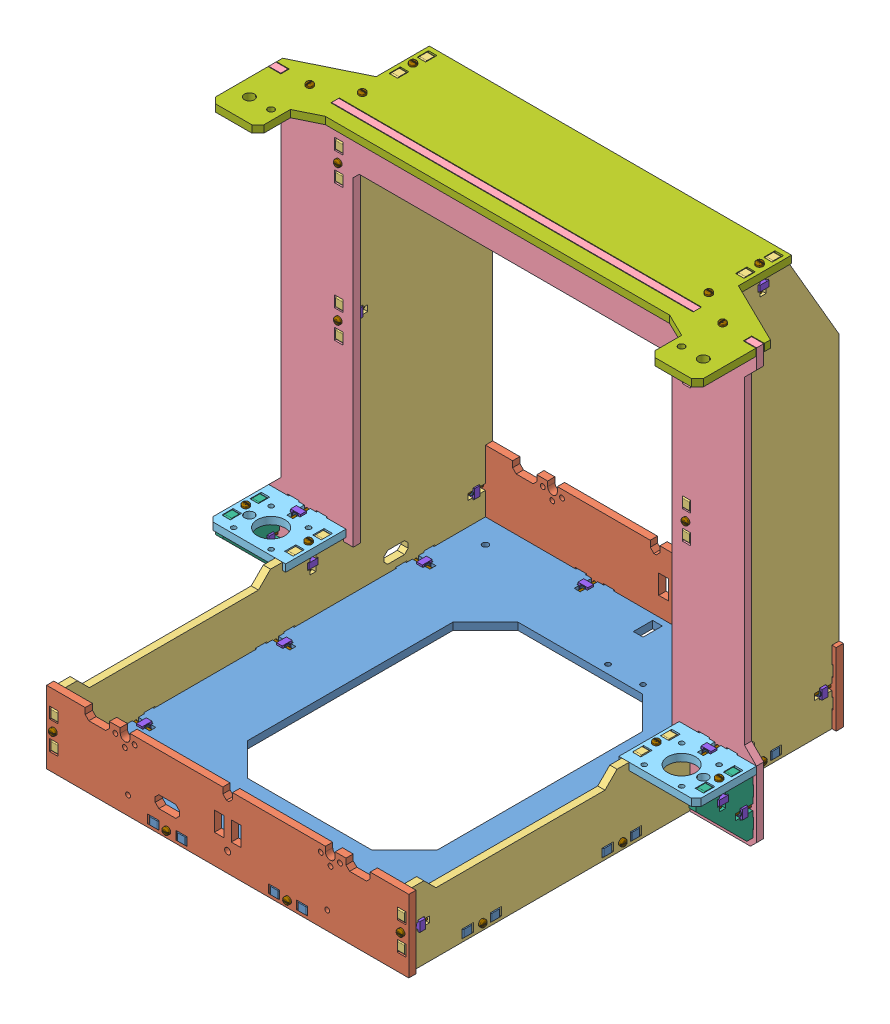
SolidWorks assembly frame, configuration default. Lengths in mm.
Overall size (404 362.48 364.96).
139 component instances, 10 part files, 72 mates.
Components (placement in the parent):
- frame_bottom-1: frame_bottom [Défaut] at origin size (293 6 360)
- frame_face-1: frame_face [front] at (0 20.5 177) size (300 60 6)
- frame_face-2: frame_face [rear] at (0 20.5 -177) size (300 60 6)
- frame_side-1: frame_side [left] at (-143.5 -5.5 0) x (-1 0 0) z (0 0 -1) size (6 360 360)
- frame_side-2: frame_side [right] at (143.5 -5.5 0) x (-1 0 0) z (0 0 -1) size (6 360 360)
- frame_middle-1: frame_middle [Défaut] at (0 314.5 -59) size (404 360 6)
- frame_z_motor-1: frame_z_motor [Défaut] at (-170 51.5 -31) x (1 0 0) z (0 0 -1)
- frame_z_motor_holder-1: frame_z_motor_holder [Défaut] at (-196 1.5 -51) x (1 0 0) z (0 0 -1)
- frame_top-1: frame_top [Défaut] at (0 348.5 -93) size (404 6 130)
- nut_fastener-1: nut_fastener [Défaut] at (-50 0.5 169) x (1 0 0) z (0 1 0) size (8.2 22.48 7.7)
  - nut-1: nut [Défaut] at origin size (8.2 4.8 7.7)
  - pan slot head_am (threaded)-1: pan slot head_am (threaded) [B18.6.7M - M3 x 0.5 x 20 Slotted PHMS --20N] at (0 -13.4 0) x (0 1 0) z (-1 0 0) size (22.48 5.6 5.6)
  - hex nut style 1_am-2: hex nut style 1_am [B18.2.4.1M - Hex nut, Style 1,  M3 x 0.5 --D-N] at (0 4.6 0) x (0 0 1) z (0 1 0) size (5.5 6.35 2.4)
- nut_fastener-2: nut_fastener [Défaut] at (-144 24.5 169) x (1 0 0) z (0 1 0) size (8.2 22.48 7.7)
  - nut-1: nut [Défaut] at origin size (8.2 4.8 7.7)
  - pan slot head_am (threaded)-1: pan slot head_am (threaded) [B18.6.7M - M3 x 0.5 x 20 Slotted PHMS --20N] at (0 -13.4 0) x (0 1 0) z (-1 0 0) size (22.48 5.6 5.6)
  - hex nut style 1_am-2: hex nut style 1_am [B18.2.4.1M - Hex nut, Style 1,  M3 x 0.5 --D-N] at (0 4.6 0) x (0 0 1) z (0 1 0) size (5.5 6.35 2.4)
- nut_fastener-3: nut_fastener [Défaut] at (-135.5 0.5 116) x (0 0 1) z (0 1 0) size (8.2 22.48 7.7)
  - nut-1: nut [Défaut] at origin size (8.2 4.8 7.7)
  - pan slot head_am (threaded)-1: pan slot head_am (threaded) [B18.6.7M - M3 x 0.5 x 20 Slotted PHMS --20N] at (0 -13.4 0) x (0 1 0) z (-1 0 0) size (22.48 5.6 5.6)
  - hex nut style 1_am-2: hex nut style 1_am [B18.2.4.1M - Hex nut, Style 1,  M3 x 0.5 --D-N] at (0 4.6 0) x (0 0 1) z (0 1 0) size (5.5 6.35 2.4)
- nut_fastener-4: nut_fastener [Défaut] at (-135.5 0.5 0) x (0 0 1) z (0 1 0) size (8.2 22.48 7.7)
  - nut-1: nut [Défaut] at origin size (8.2 4.8 7.7)
  - pan slot head_am (threaded)-1: pan slot head_am (threaded) [B18.6.7M - M3 x 0.5 x 20 Slotted PHMS --20N] at (0 -13.4 0) x (0 1 0) z (-1 0 0) size (22.48 5.6 5.6)
  - hex nut style 1_am-2: hex nut style 1_am [B18.2.4.1M - Hex nut, Style 1,  M3 x 0.5 --D-N] at (0 4.6 0) x (0 0 1) z (0 1 0) size (5.5 6.35 2.4)
- nut_fastener-5: nut_fastener [Défaut] at (-135.5 0.5 -116) x (0 0 1) z (0 1 0) size (8.2 22.48 7.7)
  - nut-1: nut [Défaut] at origin size (8.2 4.8 7.7)
  - pan slot head_am (threaded)-1: pan slot head_am (threaded) [B18.6.7M - M3 x 0.5 x 20 Slotted PHMS --20N] at (0 -13.4 0) x (0 1 0) z (-1 0 0) size (22.48 5.6 5.6)
  - hex nut style 1_am-2: hex nut style 1_am [B18.2.4.1M - Hex nut, Style 1,  M3 x 0.5 --D-N] at (0 4.6 0) x (0 0 1) z (0 1 0) size (5.5 6.35 2.4)
- nut_fastener-6: nut_fastener [Défaut] at (-50 0.5 -169) x (-1 0 0) z (0 1 0) size (8.2 22.48 7.7)
  - nut-1: nut [Défaut] at origin size (8.2 4.8 7.7)
  - pan slot head_am (threaded)-1: pan slot head_am (threaded) [B18.6.7M - M3 x 0.5 x 20 Slotted PHMS --20N] at (0 -13.4 0) x (0 1 0) z (-1 0 0) size (22.48 5.6 5.6)
  - hex nut style 1_am-2: hex nut style 1_am [B18.2.4.1M - Hex nut, Style 1,  M3 x 0.5 --D-N] at (0 4.6 0) x (0 0 1) z (0 1 0) size (5.5 6.35 2.4)
- nut_fastener-7: nut_fastener [Défaut] at (-144 43.5 -31) x (-1 0 0) z (0 0 1) size (8.2 22.48 7.7)
  - nut-1: nut [Défaut] at origin size (8.2 4.8 7.7)
  - pan slot head_am (threaded)-1: pan slot head_am (threaded) [B18.6.7M - M3 x 0.5 x 20 Slotted PHMS --20N] at (0 -13.4 0) x (0 1 0) z (-1 0 0) size (22.48 5.6 5.6)
  - hex nut style 1_am-2: hex nut style 1_am [B18.2.4.1M - Hex nut, Style 1,  M3 x 0.5 --D-N] at (0 4.6 0) x (0 0 1) z (0 1 0) size (5.5 6.35 2.4)
- nut_fastener-8: nut_fastener [Défaut] at (-196 43.5 -31) x (-1 0 0) z (0 0 1) size (8.2 22.48 7.7)
  - nut-1: nut [Défaut] at origin size (8.2 4.8 7.7)
  - pan slot head_am (threaded)-1: pan slot head_am (threaded) [B18.6.7M - M3 x 0.5 x 20 Slotted PHMS --20N] at (0 -13.4 0) x (0 1 0) z (-1 0 0) size (22.48 5.6 5.6)
  - hex nut style 1_am-2: hex nut style 1_am [B18.2.4.1M - Hex nut, Style 1,  M3 x 0.5 --D-N] at (0 4.6 0) x (0 0 1) z (0 1 0) size (5.5 6.35 2.4)
- nut_fastener-9: nut_fastener [Défaut] at (-196 23.5 -51) x (-1 0 0) z (0 1 0) size (8.2 22.48 7.7)
  - nut-1: nut [Défaut] at origin size (8.2 4.8 7.7)
  - pan slot head_am (threaded)-1: pan slot head_am (threaded) [B18.6.7M - M3 x 0.5 x 20 Slotted PHMS --20N] at (0 -13.4 0) x (0 1 0) z (-1 0 0) size (22.48 5.6 5.6)
  - hex nut style 1_am-2: hex nut style 1_am [B18.2.4.1M - Hex nut, Style 1,  M3 x 0.5 --D-N] at (0 4.6 0) x (0 0 1) z (0 1 0) size (5.5 6.35 2.4)
- nut_fastener-10: nut_fastener [Défaut] at (-170 52 -51) x (-1 0 0) z (0 1 0) size (8.2 22.48 7.7)
  - nut-1: nut [Défaut] at origin size (8.2 4.8 7.7)
  - pan slot head_am (threaded)-1: pan slot head_am (threaded) [B18.6.7M - M3 x 0.5 x 20 Slotted PHMS --20N] at (0 -13.4 0) x (0 1 0) z (-1 0 0) size (22.48 5.6 5.6)
  - hex nut style 1_am-2: hex nut style 1_am [B18.2.4.1M - Hex nut, Style 1,  M3 x 0.5 --D-N] at (0 4.6 0) x (0 0 1) z (0 1 0) size (5.5 6.35 2.4)
- nut_fastener-11: nut_fastener [Défaut] at (-144 24.5 -169) x (-1 0 0) z (0 1 0) size (8.2 22.48 7.7)
  - nut-1: nut [Défaut] at origin size (8.2 4.8 7.7)
  - pan slot head_am (threaded)-1: pan slot head_am (threaded) [B18.6.7M - M3 x 0.5 x 20 Slotted PHMS --20N] at (0 -13.4 0) x (0 1 0) z (-1 0 0) size (22.48 5.6 5.6)
  - hex nut style 1_am-2: hex nut style 1_am [B18.2.4.1M - Hex nut, Style 1,  M3 x 0.5 --D-N] at (0 4.6 0) x (0 0 1) z (0 1 0) size (5.5 6.35 2.4)
- nut_fastener-13: nut_fastener [Défaut] at (-144 201.5 -67) x (-1 0 0) z (0 -1 0) size (8.2 22.48 7.7)
  - nut-1: nut [Défaut] at origin size (8.2 4.8 7.7)
  - pan slot head_am (threaded)-1: pan slot head_am (threaded) [B18.6.7M - M3 x 0.5 x 20 Slotted PHMS --20N] at (0 -13.4 0) x (0 1 0) z (-1 0 0) size (22.48 5.6 5.6)
  - hex nut style 1_am-2: hex nut style 1_am [B18.2.4.1M - Hex nut, Style 1,  M3 x 0.5 --D-N] at (0 4.6 0) x (0 0 1) z (0 1 0) size (5.5 6.35 2.4)
- nut_fastener-14: nut_fastener [Défaut] at (-144 314.5 -67) x (-1 0 0) z (0 -1 0) size (8.2 22.48 7.7)
  - nut-1: nut [Défaut] at origin size (8.2 4.8 7.7)
  - pan slot head_am (threaded)-1: pan slot head_am (threaded) [B18.6.7M - M3 x 0.5 x 20 Slotted PHMS --20N] at (0 -13.4 0) x (0 1 0) z (-1 0 0) size (22.48 5.6 5.6)
  - hex nut style 1_am-2: hex nut style 1_am [B18.2.4.1M - Hex nut, Style 1,  M3 x 0.5 --D-N] at (0 4.6 0) x (0 0 1) z (0 1 0) size (5.5 6.35 2.4)
- nut_fastener-15: nut_fastener [Défaut] at (-143.5 343.5 -117) x (-1 0 0) z (0 0 1) size (8.2 22.48 7.7)
  - nut-1: nut [Défaut] at origin size (8.2 4.8 7.7)
  - pan slot head_am (threaded)-1: pan slot head_am (threaded) [B18.6.7M - M3 x 0.5 x 20 Slotted PHMS --20N] at (0 -13.4 0) x (0 1 0) z (-1 0 0) size (22.48 5.6 5.6)
  - hex nut style 1_am-2: hex nut style 1_am [B18.2.4.1M - Hex nut, Style 1,  M3 x 0.5 --D-N] at (0 4.6 0) x (0 0 1) z (0 1 0) size (5.5 6.35 2.4)
- nut_fastener-16: nut_fastener [Défaut] at (-143.5 343.5 -75) x (1 0 0) z (0 0 -1) size (8.2 22.48 7.7)
  - nut-1: nut [Défaut] at origin size (8.2 4.8 7.7)
  - pan slot head_am (threaded)-1: pan slot head_am (threaded) [B18.6.7M - M3 x 0.5 x 20 Slotted PHMS --20N] at (0 -13.4 0) x (0 1 0) z (-1 0 0) size (22.48 5.6 5.6)
  - hex nut style 1_am-2: hex nut style 1_am [B18.2.4.1M - Hex nut, Style 1,  M3 x 0.5 --D-N] at (0 4.6 0) x (0 0 1) z (0 1 0) size (5.5 6.35 2.4)
- nut_fastener-17: nut_fastener [Défaut] at (-171 343.5 -59) x (0 0 -1) z (-1 0 0) size (8.2 22.48 7.7)
  - nut-1: nut [Défaut] at origin size (8.2 4.8 7.7)
  - pan slot head_am (threaded)-1: pan slot head_am (threaded) [B18.6.7M - M3 x 0.5 x 20 Slotted PHMS --20N] at (0 -13.4 0) x (0 1 0) z (-1 0 0) size (22.48 5.6 5.6)
  - hex nut style 1_am-2: hex nut style 1_am [B18.2.4.1M - Hex nut, Style 1,  M3 x 0.5 --D-N] at (0 4.6 0) x (0 0 1) z (0 1 0) size (5.5 6.35 2.4)
- nut_fastener-18: nut_fastener [Défaut] at (50 0.5 169) x (-1 0 0) z (0 -1 0) size (8.2 22.48 7.7)
  - nut-1: nut [Défaut] at origin size (8.2 4.8 7.7)
  - pan slot head_am (threaded)-1: pan slot head_am (threaded) [B18.6.7M - M3 x 0.5 x 20 Slotted PHMS --20N] at (0 -13.4 0) x (0 1 0) z (-1 0 0) size (22.48 5.6 5.6)
  - hex nut style 1_am-2: hex nut style 1_am [B18.2.4.1M - Hex nut, Style 1,  M3 x 0.5 --D-N] at (0 4.6 0) x (0 0 1) z (0 1 0) size (5.5 6.35 2.4)
- nut_fastener-19: nut_fastener [Défaut] at (144 24.5 169) x (-1 0 0) z (0 -1 0) size (8.2 22.48 7.7)
  - nut-1: nut [Défaut] at origin size (8.2 4.8 7.7)
  - pan slot head_am (threaded)-1: pan slot head_am (threaded) [B18.6.7M - M3 x 0.5 x 20 Slotted PHMS --20N] at (0 -13.4 0) x (0 1 0) z (-1 0 0) size (22.48 5.6 5.6)
  - hex nut style 1_am-2: hex nut style 1_am [B18.2.4.1M - Hex nut, Style 1,  M3 x 0.5 --D-N] at (0 4.6 0) x (0 0 1) z (0 1 0) size (5.5 6.35 2.4)
- nut_fastener-20: nut_fastener [Défaut] at (135.5 0.5 116) x (0 0 1) z (0 -1 0) size (8.2 22.48 7.7)
  - nut-1: nut [Défaut] at origin size (8.2 4.8 7.7)
  - pan slot head_am (threaded)-1: pan slot head_am (threaded) [B18.6.7M - M3 x 0.5 x 20 Slotted PHMS --20N] at (0 -13.4 0) x (0 1 0) z (-1 0 0) size (22.48 5.6 5.6)
  - hex nut style 1_am-2: hex nut style 1_am [B18.2.4.1M - Hex nut, Style 1,  M3 x 0.5 --D-N] at (0 4.6 0) x (0 0 1) z (0 1 0) size (5.5 6.35 2.4)
- nut_fastener-21: nut_fastener [Défaut] at (135.5 0.5 0) x (0 0 1) z (0 -1 0) size (8.2 22.48 7.7)
  - nut-1: nut [Défaut] at origin size (8.2 4.8 7.7)
  - pan slot head_am (threaded)-1: pan slot head_am (threaded) [B18.6.7M - M3 x 0.5 x 20 Slotted PHMS --20N] at (0 -13.4 0) x (0 1 0) z (-1 0 0) size (22.48 5.6 5.6)
  - hex nut style 1_am-2: hex nut style 1_am [B18.2.4.1M - Hex nut, Style 1,  M3 x 0.5 --D-N] at (0 4.6 0) x (0 0 1) z (0 1 0) size (5.5 6.35 2.4)
- nut_fastener-22: nut_fastener [Défaut] at (135.5 0.5 -116) x (0 0 1) z (0 -1 0) size (8.2 22.48 7.7)
  - nut-1: nut [Défaut] at origin size (8.2 4.8 7.7)
  - pan slot head_am (threaded)-1: pan slot head_am (threaded) [B18.6.7M - M3 x 0.5 x 20 Slotted PHMS --20N] at (0 -13.4 0) x (0 1 0) z (-1 0 0) size (22.48 5.6 5.6)
  - hex nut style 1_am-2: hex nut style 1_am [B18.2.4.1M - Hex nut, Style 1,  M3 x 0.5 --D-N] at (0 4.6 0) x (0 0 1) z (0 1 0) size (5.5 6.35 2.4)
- nut_fastener-23: nut_fastener [Défaut] at (50 0.5 -169) x (1 0 0) z (0 -1 0) size (8.2 22.48 7.7)
  - nut-1: nut [Défaut] at origin size (8.2 4.8 7.7)
  - pan slot head_am (threaded)-1: pan slot head_am (threaded) [B18.6.7M - M3 x 0.5 x 20 Slotted PHMS --20N] at (0 -13.4 0) x (0 1 0) z (-1 0 0) size (22.48 5.6 5.6)
  - hex nut style 1_am-2: hex nut style 1_am [B18.2.4.1M - Hex nut, Style 1,  M3 x 0.5 --D-N] at (0 4.6 0) x (0 0 1) z (0 1 0) size (5.5 6.35 2.4)
- nut_fastener-24: nut_fastener [Défaut] at (144 43.5 -31) x (1 0 0) z (0 0 -1) size (8.2 22.48 7.7)
  - nut-1: nut [Défaut] at origin size (8.2 4.8 7.7)
  - pan slot head_am (threaded)-1: pan slot head_am (threaded) [B18.6.7M - M3 x 0.5 x 20 Slotted PHMS --20N] at (0 -13.4 0) x (0 1 0) z (-1 0 0) size (22.48 5.6 5.6)
  - hex nut style 1_am-2: hex nut style 1_am [B18.2.4.1M - Hex nut, Style 1,  M3 x 0.5 --D-N] at (0 4.6 0) x (0 0 1) z (0 1 0) size (5.5 6.35 2.4)
- nut_fastener-25: nut_fastener [Défaut] at (196 43.5 -31) x (1 0 0) z (0 0 -1) size (8.2 22.48 7.7)
  - nut-1: nut [Défaut] at origin size (8.2 4.8 7.7)
  - pan slot head_am (threaded)-1: pan slot head_am (threaded) [B18.6.7M - M3 x 0.5 x 20 Slotted PHMS --20N] at (0 -13.4 0) x (0 1 0) z (-1 0 0) size (22.48 5.6 5.6)
  - hex nut style 1_am-2: hex nut style 1_am [B18.2.4.1M - Hex nut, Style 1,  M3 x 0.5 --D-N] at (0 4.6 0) x (0 0 1) z (0 1 0) size (5.5 6.35 2.4)
- nut_fastener-26: nut_fastener [Défaut] at (196 23.5 -51) x (1 0 0) z (0 -1 0) size (8.2 22.48 7.7)
  - nut-1: nut [Défaut] at origin size (8.2 4.8 7.7)
  - pan slot head_am (threaded)-1: pan slot head_am (threaded) [B18.6.7M - M3 x 0.5 x 20 Slotted PHMS --20N] at (0 -13.4 0) x (0 1 0) z (-1 0 0) size (22.48 5.6 5.6)
  - hex nut style 1_am-2: hex nut style 1_am [B18.2.4.1M - Hex nut, Style 1,  M3 x 0.5 --D-N] at (0 4.6 0) x (0 0 1) z (0 1 0) size (5.5 6.35 2.4)
- nut_fastener-27: nut_fastener [Défaut] at (170 52 -51) x (1 0 0) z (0 -1 0) size (8.2 22.48 7.7)
  - nut-1: nut [Défaut] at origin size (8.2 4.8 7.7)
  - pan slot head_am (threaded)-1: pan slot head_am (threaded) [B18.6.7M - M3 x 0.5 x 20 Slotted PHMS --20N] at (0 -13.4 0) x (0 1 0) z (-1 0 0) size (22.48 5.6 5.6)
  - hex nut style 1_am-2: hex nut style 1_am [B18.2.4.1M - Hex nut, Style 1,  M3 x 0.5 --D-N] at (0 4.6 0) x (0 0 1) z (0 1 0) size (5.5 6.35 2.4)
- nut_fastener-28: nut_fastener [Défaut] at (144 24.5 -169) x (1 0 0) z (0 -1 0) size (8.2 22.48 7.7)
  - nut-1: nut [Défaut] at origin size (8.2 4.8 7.7)
  - pan slot head_am (threaded)-1: pan slot head_am (threaded) [B18.6.7M - M3 x 0.5 x 20 Slotted PHMS --20N] at (0 -13.4 0) x (0 1 0) z (-1 0 0) size (22.48 5.6 5.6)
  - hex nut style 1_am-2: hex nut style 1_am [B18.2.4.1M - Hex nut, Style 1,  M3 x 0.5 --D-N] at (0 4.6 0) x (0 0 1) z (0 1 0) size (5.5 6.35 2.4)
- nut_fastener-29: nut_fastener [Défaut] at (144 201.5 -67) x (1 0 0) z (0 1 0) size (8.2 22.48 7.7)
  - nut-1: nut [Défaut] at origin size (8.2 4.8 7.7)
  - pan slot head_am (threaded)-1: pan slot head_am (threaded) [B18.6.7M - M3 x 0.5 x 20 Slotted PHMS --20N] at (0 -13.4 0) x (0 1 0) z (-1 0 0) size (22.48 5.6 5.6)
  - hex nut style 1_am-2: hex nut style 1_am [B18.2.4.1M - Hex nut, Style 1,  M3 x 0.5 --D-N] at (0 4.6 0) x (0 0 1) z (0 1 0) size (5.5 6.35 2.4)
- nut_fastener-30: nut_fastener [Défaut] at (144 314.5 -67) x (1 0 0) z (0 1 0) size (8.2 22.48 7.7)
  - nut-1: nut [Défaut] at origin size (8.2 4.8 7.7)
  - pan slot head_am (threaded)-1: pan slot head_am (threaded) [B18.6.7M - M3 x 0.5 x 20 Slotted PHMS --20N] at (0 -13.4 0) x (0 1 0) z (-1 0 0) size (22.48 5.6 5.6)
  - hex nut style 1_am-2: hex nut style 1_am [B18.2.4.1M - Hex nut, Style 1,  M3 x 0.5 --D-N] at (0 4.6 0) x (0 0 1) z (0 1 0) size (5.5 6.35 2.4)
- nut_fastener-31: nut_fastener [Défaut] at (143.5 343.5 -117) x (1 0 0) z (0 0 -1) size (8.2 22.48 7.7)
  - nut-1: nut [Défaut] at origin size (8.2 4.8 7.7)
  - pan slot head_am (threaded)-1: pan slot head_am (threaded) [B18.6.7M - M3 x 0.5 x 20 Slotted PHMS --20N] at (0 -13.4 0) x (0 1 0) z (-1 0 0) size (22.48 5.6 5.6)
  - hex nut style 1_am-2: hex nut style 1_am [B18.2.4.1M - Hex nut, Style 1,  M3 x 0.5 --D-N] at (0 4.6 0) x (0 0 1) z (0 1 0) size (5.5 6.35 2.4)
- nut_fastener-32: nut_fastener [Défaut] at (143.5 343.5 -75) x (-1 0 0) z (0 0 1) size (8.2 22.48 7.7)
  - nut-1: nut [Défaut] at origin size (8.2 4.8 7.7)
  - pan slot head_am (threaded)-1: pan slot head_am (threaded) [B18.6.7M - M3 x 0.5 x 20 Slotted PHMS --20N] at (0 -13.4 0) x (0 1 0) z (-1 0 0) size (22.48 5.6 5.6)
  - hex nut style 1_am-2: hex nut style 1_am [B18.2.4.1M - Hex nut, Style 1,  M3 x 0.5 --D-N] at (0 4.6 0) x (0 0 1) z (0 1 0) size (5.5 6.35 2.4)
- nut_fastener-33: nut_fastener [Défaut] at (171 343.5 -59) x (0 0 -1) z (-1 0 0) size (8.2 22.48 7.7)
  - nut-1: nut [Défaut] at origin size (8.2 4.8 7.7)
  - pan slot head_am (threaded)-1: pan slot head_am (threaded) [B18.6.7M - M3 x 0.5 x 20 Slotted PHMS --20N] at (0 -13.4 0) x (0 1 0) z (-1 0 0) size (22.48 5.6 5.6)
  - hex nut style 1_am-2: hex nut style 1_am [B18.2.4.1M - Hex nut, Style 1,  M3 x 0.5 --D-N] at (0 4.6 0) x (0 0 1) z (0 1 0) size (5.5 6.35 2.4)
- frame_z_motor-3: frame_z_motor [Défaut] at (170 51.5 -31) x (-1 0 0) z (0 0 -1)
- frame_z_motor_holder-3: frame_z_motor_holder [Défaut] at (196 1.5 -51) x (1 0 0) z (0 0 -1)
Mates (geometry in assembly coordinates):
- Coïncidente2: coincident anti-aligned: plane of frame_bottom-1 through (-140.5 3 174) normal (0 0 1); plane of frame_face-1 through (-85 50.5 174) normal (0 0 -1)
- Coïncidente5: coincident anti-aligned: plane of frame_bottom-1 through (0 -3 0) normal (0 -1 0); plane of frame_face-1 through (-66.3 -3 180) normal (0 1 0)
- Coïncidente7: coincident anti-aligned: plane of frame_bottom-1 through (-140.5 3 -174) normal (0 0 -1); plane of frame_face-2 through (-85 50.5 -174) normal (0 0 1)
- Coïncidente17: coincident anti-aligned: plane of frame_bottom-1 through (0 -3 0) normal (0 -1 0); plane of frame_side-1 through (-146.5 -3 -99.7) normal (0 1 0)
- Coïncidente20: coincident anti-aligned: plane of frame_bottom-1 through (0 -3 0) normal (0 -1 0); plane of frame_side-2 through (140.5 -3 -132.3) normal (0 1 0)
- Coïncidente21: coincident anti-aligned: plane of frame_bottom-1 through (140.5 3 -174) normal (1 0 0); plane of frame_side-2 through (140.5 -5.5 0) normal (-1 0 0)
- Coïncidente22: coincident anti-aligned: plane of frame_bottom-1 through (-140.5 3 -174) normal (-1 0 0); plane of frame_side-1 through (-140.5 -5.5 0) normal (1 0 0)
- Coïncidente24: coincident anti-aligned: plane of frame_side-1 through (-146.5 348.5 -62) normal (0 0 1); plane of frame_middle-1 through (0 314.5 -62) normal (0 0 -1)
- Coïncidente25: coincident anti-aligned: plane of frame_side-1 through (-146.5 48.5 -62) normal (0 1 0); plane of frame_middle-1 through (-147 48.5 -56) normal (0 -1 0)
- Coïncidente41: coincident anti-aligned: plane of frame_side-1 through (-146.5 48.5 -62) normal (0 1 0); plane of frame_z_motor-1 through (-170 48.5 -31) normal (0 -1 0)
- Coïncidente44: coincident anti-aligned: plane of frame_middle-1 through (0 314.5 -56) normal (0 0 1); plane of frame_z_motor-1 through (-202 48.5 -56) normal (0 0 -1)
- Coïncidente45: coincident anti-aligned: line of frame_middle-1 through (-202 54.5 -56) axis (0 -1 0); line of frame_z_motor-1 through (-202 48.5 -56) axis (0 1 0)
- Coïncidente46: coincident anti-aligned: plane of frame_middle-1 through (0 314.5 -56) normal (0 0 1); plane of frame_z_motor_holder-1 through (-193 48.5 -56) normal (0 0 -1)
- Coïncidente47: coincident anti-aligned: plane of frame_z_motor-1 through (-170 48.5 -31) normal (0 -1 0); plane of frame_z_motor_holder-1 through (-193 48.5 -9) normal (0 1 0)
- Distance2: distance = 0.5 mm: line of frame_z_motor_holder-1 through (-193 54.5 -45.5) axis (0 0 1); line of frame_z_motor-1 through (-192.5 54.5 -47.3) axis (0 0 1)
- Coïncidente39: coincident anti-aligned: plane of frame_side-1 through (-146.5 348.5 -137) normal (0 1 0); plane of frame_top-1 through (0 348.5 -93) normal (0 -1 0)
- Coïncidente40: coincident anti-aligned: line of frame_side-1 through (-146.5 348.5 -137) axis (1 0 0); line of frame_top-1 through (150 348.5 -137) axis (-1 0 0)
- Coïncidente48: coincident aligned: plane of frame_face-1 through (0 20.5 177) normal (1 0 0); plane of assembly through (0 0 0) normal (1 0 0)
- Coïncidente49: coincident aligned: plane of frame_face-2 through (0 20.5 -177) normal (1 0 0); plane of assembly through (0 0 0) normal (1 0 0)
- Coïncidente50: coincident anti-aligned: plane of frame_side-1 through (-143.5 -5.5 0) normal (0 0 -1); plane of assembly through (0 0 0) normal (0 0 1)
- Coïncidente51: coincident anti-aligned: plane of frame_side-2 through (143.5 -5.5 0) normal (0 0 -1); plane of assembly through (0 0 0) normal (0 0 1)
- Coïncidente52: coincident aligned: plane of frame_middle-1 through (0 314.5 -59) normal (1 0 0); plane of assembly through (0 0 0) normal (1 0 0)
- Coïncidente53: coincident aligned: plane of frame_top-1 through (0 348.5 -93) normal (1 0 0); plane of assembly through (0 0 0) normal (1 0 0)
- Coaxiale1: concentric aligned: circle of frame_face-1; cylinder of nut_fastener-1/pan slot head_am (threaded)-1 through (-50 0.5 207.8) axis (0 0 1) radius 1.5
- Coïncidente54: coincident anti-aligned: plane of frame_face-1 through (-85 50.5 180) normal (0 0 1); plane of nut_fastener-1/pan slot head_am (threaded)-1 through (-50 -1 180) normal (0 0 -1)
- Parallèle1: parallel aligned: plane of frame_bottom-1 through (0 3 0) normal (0 1 0); plane of nut_fastener-1/nut-1 through (-50 4.35 164.2) normal (0 1 0)
- Coaxiale2: concentric aligned: circle of frame_face-1; cylinder of nut_fastener-2/pan slot head_am (threaded)-1 through (-144 24.5 207.8) axis (0 0 1) radius 1.5
- Coïncidente55: coincident anti-aligned: plane of frame_face-1 through (-85 50.5 180) normal (0 0 1); plane of nut_fastener-2/pan slot head_am (threaded)-1 through (-144 23 180) normal (0 0 -1)
- Parallèle2: parallel aligned: plane of frame_side-1 through (-146.5 -5.5 0) normal (-1 0 0); plane of nut_fastener-2/nut-1 through (-148.1 24.5 164.2) normal (-1 0 0)
- Coaxiale3: concentric aligned: circle of frame_side-1; cylinder of nut_fastener-3/pan slot head_am (threaded)-1 through (-174.3 0.5 116) axis (-1 0 0) radius 1.5
- Coïncidente56: coincident aligned: plane of frame_side-1 through (-146.5 -5.5 0) normal (-1 0 0); circle of nut_fastener-3/pan slot head_am (threaded)-1
- Parallèle3: parallel aligned: plane of frame_bottom-1 through (0 3 0) normal (0 1 0); plane of nut_fastener-3/nut-1 through (-130.7 4.35 116) normal (0 1 0)
- Coaxiale4: concentric anti-aligned: cylinder of frame_side-1 through (-146.5 0.5 0) axis (1 0 0) radius 1.8; cylinder of nut_fastener-4/pan slot head_am (threaded)-1 through (-174.3 0.5 0) axis (-1 0 0) radius 1.5
- Coïncidente57: coincident anti-aligned: plane of frame_side-1 through (-146.5 -5.5 0) normal (-1 0 0); plane of nut_fastener-4/pan slot head_am (threaded)-1 through (-146.5 -1 0) normal (1 0 0)
- Parallèle4: parallel aligned: plane of frame_bottom-1 through (0 3 0) normal (0 1 0); plane of nut_fastener-4/nut-1 through (-130.7 4.35 0) normal (0 1 0)
- Coaxiale5: concentric aligned: circle of frame_side-1; cylinder of nut_fastener-5/pan slot head_am (threaded)-1 through (-174.3 0.5 -116) axis (-1 0 0) radius 1.5
- Coïncidente58: coincident aligned: plane of frame_side-1 through (-146.5 -5.5 0) normal (-1 0 0); circle of nut_fastener-5/pan slot head_am (threaded)-1
- Parallèle5: parallel aligned: plane of frame_bottom-1 through (0 3 0) normal (0 1 0); plane of nut_fastener-5/nut-1 through (-130.7 4.35 -116) normal (0 1 0)
- Coaxiale6: concentric aligned: cylinder of frame_face-2 through (-50 0.5 -174) axis (0 0 -1) radius 1.8; cylinder of nut_fastener-6/pan slot head_am (threaded)-1 through (-50 0.5 -207.8) axis (0 0 -1) radius 1.5
- Coïncidente59: coincident aligned: plane of frame_face-2 through (-85 50.5 -180) normal (0 0 -1); circle of nut_fastener-6/pan slot head_am (threaded)-1
- Parallèle6: parallel aligned: plane of frame_bottom-1 through (0 3 0) normal (0 1 0); plane of nut_fastener-6/nut-1 through (-50 4.35 -164.2) normal (0 1 0)
- Coaxiale7: concentric anti-aligned: circle of frame_z_motor-1; cylinder of nut_fastener-7/pan slot head_am (threaded)-1 through (-144 82.3 -31) axis (0 1 0) radius 1.5
- Coïncidente60: coincident aligned: plane of frame_z_motor-1 through (-170 54.5 -31) normal (0 1 0); circle of nut_fastener-7/pan slot head_am (threaded)-1
- Parallèle7: parallel aligned: plane of frame_side-1 through (-140.5 -5.5 0) normal (1 0 0); plane of nut_fastener-7/nut-1 through (-139.9 38.7 -31) normal (1 0 0)
- Coaxiale8: concentric aligned: cylinder of frame_z_motor-1 through (-196 48.5 -31) axis (0 1 0) radius 1.8; cylinder of nut_fastener-8/pan slot head_am (threaded)-1 through (-196 82.3 -31) axis (0 1 0) radius 1.5
- Coïncidente61: coincident aligned: plane of frame_z_motor-1 through (-170 54.5 -31) normal (0 1 0); circle of nut_fastener-8/pan slot head_am (threaded)-1
- Parallèle8: parallel aligned: plane of frame_z_motor_holder-1 through (-199 1.5 -51) normal (-1 0 0); plane of nut_fastener-8/nut-1 through (-200.1 38.7 -31) normal (-1 0 0)
- Coaxiale9: concentric anti-aligned: circle of frame_middle-1; cylinder of nut_fastener-9/pan slot head_am (threaded)-1 through (-196 23.5 -89.8) axis (0 0 -1) radius 1.5
- Coïncidente62: coincident aligned: plane of frame_middle-1 through (0 314.5 -62) normal (0 0 -1); circle of nut_fastener-9/pan slot head_am (threaded)-1
- Parallèle9: parallel aligned: plane of frame_z_motor_holder-1 through (-199 1.5 -51) normal (-1 0 0); plane of nut_fastener-9/nut-1 through (-200.1 23.5 -46.2) normal (-1 0 0)
- Coaxiale10: concentric anti-aligned: cylinder of frame_middle-1 through (-170 52 -62.001) axis (0 0 1) radius 1.8; cylinder of nut_fastener-10/pan slot head_am (threaded)-1 through (-170 52 -89.8) axis (0 0 -1) radius 1.5
- Coïncidente63: coincident aligned: plane of frame_middle-1 through (0 314.5 -62) normal (0 0 -1); circle of nut_fastener-10/pan slot head_am (threaded)-1
- Parallèle10: parallel aligned: plane of frame_z_motor-1 through (-170 54.5 -31) normal (0 1 0); plane of nut_fastener-10/nut-1 through (-170 55.85 -46.2) normal (0 1 0)
- Coaxiale11: concentric anti-aligned: circle of frame_face-2; cylinder of nut_fastener-11/pan slot head_am (threaded)-1 through (-144 24.5 -207.8) axis (0 0 -1) radius 1.5
- Coïncidente64: coincident aligned: plane of frame_face-2 through (-85 50.5 -180) normal (0 0 -1); circle of nut_fastener-11/pan slot head_am (threaded)-1
- Parallèle11: parallel aligned: plane of frame_side-1 through (-146.5 -5.5 0) normal (-1 0 0); plane of nut_fastener-11/nut-1 through (-148.1 24.5 -164.2) normal (-1 0 0)
- Coaxiale13: concentric aligned: cylinder of frame_middle-1 through (-144 201.5 -62.001) axis (0 0 1) radius 1.8; cylinder of nut_fastener-13/pan slot head_am (threaded)-1 through (-144 201.5 -28.2) axis (0 0 1) radius 1.5
- Coïncidente65: coincident anti-aligned: plane of frame_middle-1 through (0 314.5 -56) normal (0 0 1); plane of nut_fastener-13/pan slot head_am (threaded)-1 through (-144 203 -56) normal (0 0 -1)
- Parallèle12: parallel aligned: plane of frame_side-1 through (-146.5 -5.5 0) normal (-1 0 0); plane of nut_fastener-13/nut-1 through (-148.1 201.5 -71.8) normal (-1 0 0)
- Coaxiale14: concentric aligned: circle of frame_middle-1; cylinder of nut_fastener-14/pan slot head_am (threaded)-1 through (-144 314.5 -28.2) axis (0 0 1) radius 1.5
- Coïncidente67: coincident aligned: plane of frame_middle-1 through (0 314.5 -56) normal (0 0 1); circle of nut_fastener-14/pan slot head_am (threaded)-1
- Parallèle13: parallel aligned: plane of frame_side-1 through (-146.5 -5.5 0) normal (-1 0 0); plane of nut_fastener-14/nut-1 through (-148.1 314.5 -71.8) normal (-1 0 0)
- Coaxiale15: concentric aligned: circle of frame_top-1; cylinder of nut_fastener-15/pan slot head_am (threaded)-1 through (-143.5 382.3 -117) axis (0 1 0) radius 1.5
- Coïncidente68: coincident aligned: plane of frame_top-1 through (0 354.5 -93) normal (0 1 0); circle of nut_fastener-15/pan slot head_am (threaded)-1
- Parallèle14: parallel aligned: plane of frame_side-1 through (-146.5 -5.5 0) normal (-1 0 0); plane of nut_fastener-15/nut-1 through (-147.6 338.7 -117) normal (-1 0 0)
- Coaxiale161: concentric anti-aligned: cylinder of frame_top-1 through (-143.5 354.5 -75) axis (0 -1 0) radius 2; cylinder of nut_fastener-16/pan slot head_am (threaded)-1 through (-143.5 382.3 -75) axis (0 1 0) radius 2.8
- Coïncidente691: coincident anti-aligned: plane of frame_top-1 through (0 354.5 -93) normal (0 1 0); plane of nut_fastener-16/pan slot head_am (threaded)-1 through (-143.5 354.5 -73.5) normal (0 -1 0)
- Parallèle15: parallel aligned: plane of frame_side-1 through (-146.5 -5.5 0) normal (-1 0 0); plane of nut_fastener-16/nut-1 through (-147.6 338.7 -75) normal (-1 0 0)
- Coaxiale171: concentric anti-aligned: cylinder of frame_top-1 through (-171 354.5 -59) axis (0 -1 0) radius 2; cylinder of nut_fastener-17/pan slot head_am (threaded)-1 through (-171 382.3 -59) axis (0 1 0) radius 2.8
- Coïncidente701: coincident anti-aligned: plane of frame_top-1 through (0 354.5 -93) normal (0 1 0); plane of nut_fastener-17/pan slot head_am (threaded)-1 through (-169.5 354.5 -59) normal (0 -1 0)
- Parallèle16: parallel aligned: plane of frame_middle-1 through (0 314.5 -56) normal (0 0 1); plane of nut_fastener-17/nut-1 through (-171 338.7 -54.9) normal (0 0 1)
- Coïncidente703: coincident anti-aligned: plane of frame_face-2 through (150 54.5 -174) normal (0 1 0); plane of frame_side-2 through (140.5 54.5 -180) normal (0 -1 0)
